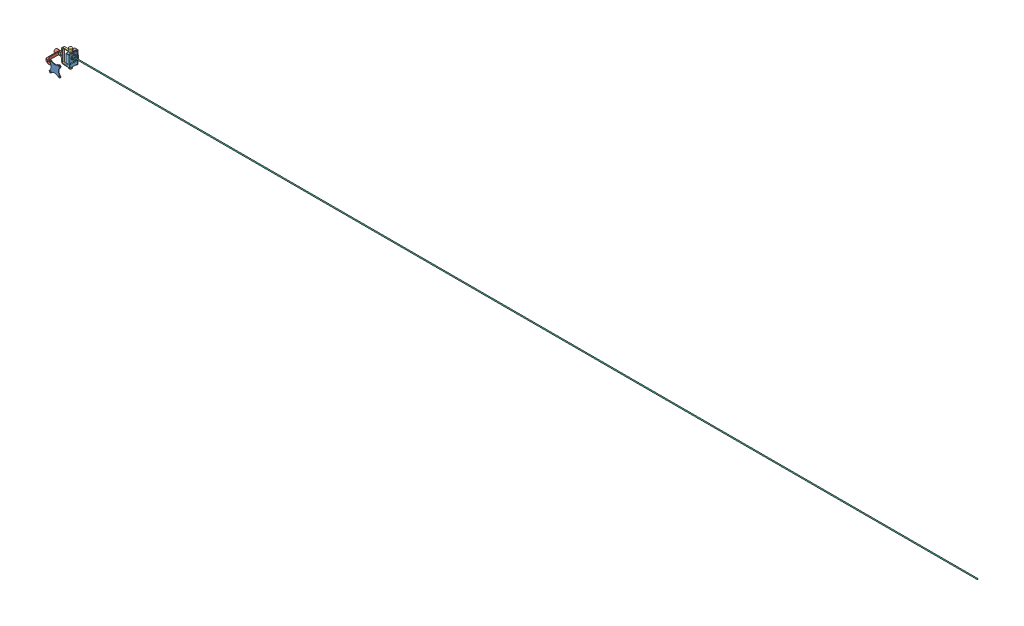
SolidWorks assembly Assembly, configuration Default. Lengths in mm.
Overall size (10197.5 1085 1025).
7 component instances, 6 part files, 19 mates.
Components (placement in the parent):
- Base-1: Base [Default] at (0 0 1000) x (1 0 0) z (0 0 -1) size (124.69 124.69 40)
- Link1-1: Link1 [Default] at (-130 0 845) x (1 0 0) z (0 0 -1) size (190 40 175)
- Link2-1: Link2 [Default] at (-5 72 845) x (1 0 0) z (0 0 -1) size (177.5 195 35)
- Assem1^Assembly-1: Assem1^Assembly [Default] at (27.5 23 830.9521) x (1 0 0) z (0 0 -1) size (61.5 182 98) (virtual)
  - Link3-1: Link3 [Default] at (-32.5 -41 -14.0479) size (44.83 182 75)
  - Tool-1: Tool [Default] at origin size (61.5 128 93)
- Light-1: Light [Default] at (27.5 23 830.9521) x (1 0 0) z (0 0 -1) size (10000 10 10)
Mates (geometry in assembly coordinates):
- Parallel4: parallel anti-aligned: plane of Base-1 through (0 0 1000) normal (0 0 -1); plane of assembly through (0 0 0) normal (0 0 1)
- Coincident11: coincident anti-aligned: plane of Base-1 through (0 0 1000) normal (0 -1 0); plane of assembly through (0 0 0) normal (0 1 0)
- Coincident2: coincident aligned: plane of Base-1 through (0 0 1000) normal (1 0 0); plane of assembly through (0 0 0) normal (1 0 0)
- Concentric1: concentric aligned: cylinder of Base-1 through (0 0 990) axis (0 0 1) radius 15; cylinder of Link1-1 through (0 0 990) axis (0 0 1) radius 15
- Coincident3: coincident anti-aligned: plane of Base-1 through (0 0 1000) normal (0 0 -1); plane of Link1-1 through (0 0 1000) normal (0 0 1)
- Distance1: distance = 1000 mm: point of Base-1; point of assembly
- Concentric2: concentric anti-aligned: cylinder of Link1-1 through (-140 0 845) axis (1 0 0) radius 10; cylinder of Link2-1 through (-130 0 845) axis (-1 0 0) radius 10
- Coincident4: coincident anti-aligned: plane of Link1-1 through (-130 15 860) normal (1 0 0); plane of Link2-1 through (-130 0 845) normal (-1 0 0)
- Concentric3: concentric anti-aligned: cylinder of Link2-1 through (-5 72 845) axis (0 1 0) radius 5; cylinder of Assem1^Assembly-1/Link3-1 through (-5 100 845) axis (0 -1 0) radius 5
- Coincident5: coincident anti-aligned: plane of Link2-1 through (-20 72 855) normal (0 -1 0); plane of Assem1^Assembly-1/Link3-1 through (12.5 72 785.9521) normal (0 1 0)
- Coincident6: coincident anti-aligned: plane of Link1-1 through (-130 0 845) normal (0 -1 0); plane of assembly through (0 0 0) normal (0 1 0)
- Coincident7: coincident aligned: plane of Link1-1 through (-130 0 845) normal (0 0 -1); plane of Link2-1 through (-5 72 845) normal (0 0 -1)
- Parallel3: parallel aligned: plane of Link2-1 through (-5 72 845) normal (1 0 0); plane of Assem1^Assembly-1/Tool-1 through (27.5 23 830.9521) normal (1 0 0)
- Angle3: planar angle = 0.769133 rad anti-aligned: plane of Link1-1 through (-93.4068 -90.4167 845) normal (0.695513 -0.718514 0); plane of assembly through (0 0 0) normal (0 1 0)
- Angle4: planar angle = 2.617994 rad anti-aligned: plane of Link2-1 through (-58.9954 -41.5758 3845) normal (0 0 -1); plane of Link1-1 through (67.3454 -111.1962 3845) normal (0 0 -1)
- Angle5: planar angle = 0.528582 rad aligned: plane of Link2-1 through (-53.6695 48.2554 845) normal (0 0 -1); plane of Assem1^Assembly-1 through (-4.5149 27.6401 816.4793) normal (-0.362353 -0.350753 -0.863523)
- Coincident12: coordinate: point of Assem1^Assembly-1/Tool-1; point of Light-1
- Concentric5: concentric: cylinder of ? through (2489.9197 2442.2266 -5559.9301) axis (-0.251081 -0.243043 0.936957) radius 5
- Concentric7: concentric: cylinder of ? through (1195.2196 1151.3945 -6048.4779) axis (-0.122073 -0.114378 0.985909) radius 5
